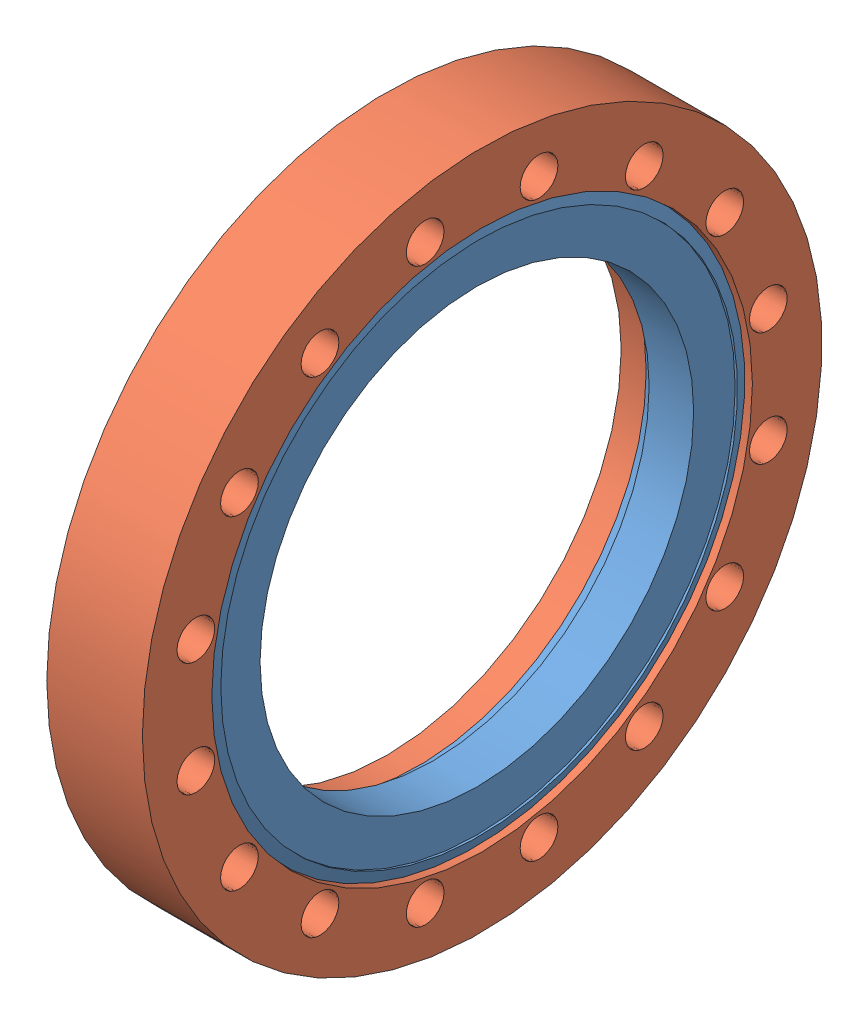
SolidWorks assembly 100026 (6.0 X 4.0 R), configuration Default. Lengths in mm.
Overall size (21.34 151.64 151.64).
2 component instances, 2 part files, 0 mates.
Components (placement in the parent):
- 100026 (6.0 X 4.0 INS)-1: 100026 (6.0 X 4.0 INS) [Default] at origin size (13.64 120.4 120.4)
- 100026 (6.0 X 4.0 REC)-1: 100026 (6.0 X 4.0 REC) [Default] at (-7.0358 0 0) x (1 0 0) z (0 0 -1) size (21.34 151.64 151.64)
